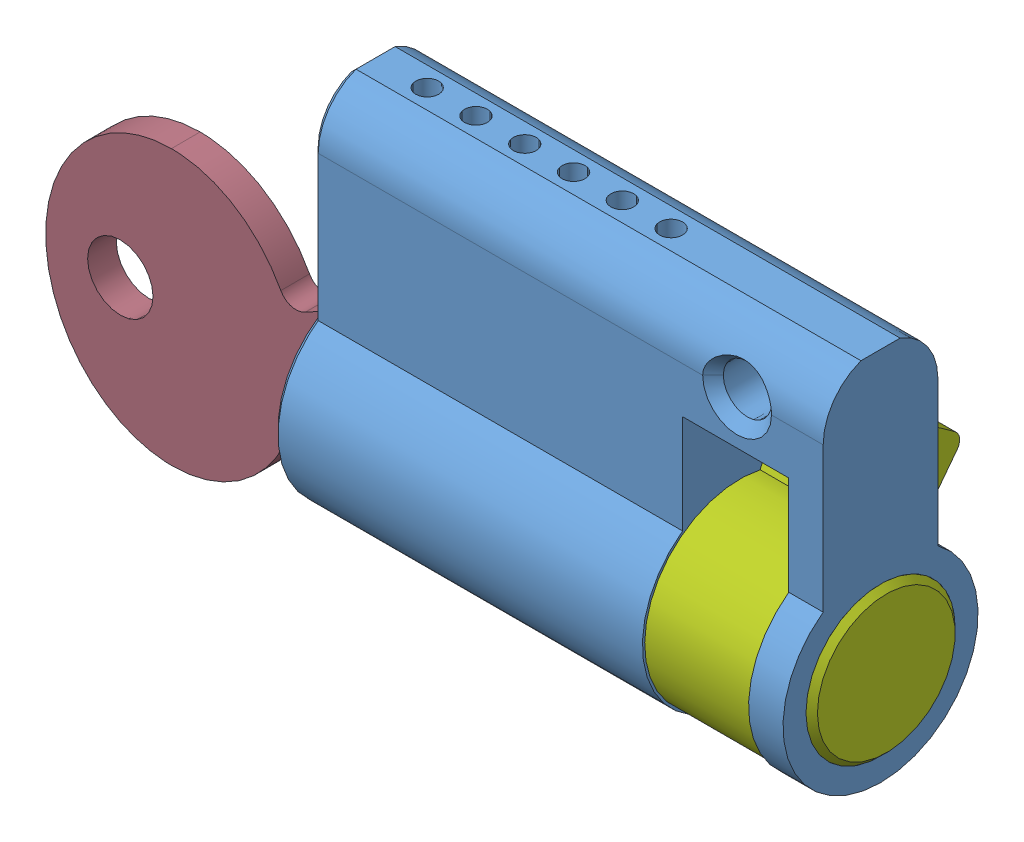
SolidWorks assembly lock_6-pin_assembly_eg, configuration Default. Lengths in mm.
Overall size (72.78 39.27 18.49).
16 component instances, 13 part files, 0 mates.
Components (placement in the parent):
- cylinder_6-pin_sub-assembly_e-1: cylinder_6-pin_sub-assembly_e [Default] at origin size (44.5 32.7 17)
  - cylinder_d_six-pair_of_pins-1: cylinder_d_six-pair_of_pins [Default] at origin size (44.5 32.7 17)
  - upper_half_pin_y_cut_depth_2-1: upper_half_pin_y_cut_depth_2 [Default] at (5 15.25 0) x (0.989024 0 0.147752) z (0 -1 0) size (2 2 8)
  - upper_half_pin_y_cut_depth_4-1: upper_half_pin_y_cut_depth_4 [Default] at (9.25 13.25 0) x (0.53788 0 0.843022) z (0 -1 0) size (2 2 6)
  - upper_half_pin_y_cut_depth_5-1: upper_half_pin_y_cut_depth_5 [Default] at (13.5 12.25 0) x (0.923388 0 0.383868) z (0 -1 0) size (2 2 5)
  - upper_half_pin_y_cut_depth_1-1: upper_half_pin_y_cut_depth_1 [Default] at (22 16.4 0) x (-0.223246 0 0.974762) z (0 -1 0) size (2 2 9.15)
  - upper_half_pin_y_cut_depth_3-1: upper_half_pin_y_cut_depth_3 [Default] at (26.25 14.25 0) x (-0.197827 0 0.980237) z (0 -1 0) size (2 2 7)
- core_6-pin_with_key_g-1: core_6-pin_with_key_g [Default] x (1 0 0) z (0 -0.003633 0.999993) size (72.78 29.23 18.24)
  - core_6-pin_sub-assembly_cxxxxxx-1: core_6-pin_sub-assembly_cxxxxxx [Default] at origin size (45.22 22.49 18.24)
    - core_c_six-pair_of_pins-1: core_c_six-pair_of_pins [Default] at origin size (45.22 22.49 18.24)
    - lower_half_pin_x-depth_2-1: lower_half_pin_x-depth_2 [Default] at (5 7.25 0) x (0.664735 0 0.74708) z (-0.74708 0 0.664735) size (2.04 6.1 2.04)
    - lower_half_pin_x-depth_4-1: lower_half_pin_x-depth_4 [Default] at (9.25 7.25 0) x (0.344742 0 0.938697) z (-0.938697 0 0.344742) size (2.04 8.1 2.04)
    - lower_half_pin_x-depth_5-1: lower_half_pin_x-depth_5 [Default] at (13.5 7.25 0) x (-0.232518 0 0.972592) z (-0.972592 0 -0.232518) size (2.04 9.1 2.04)
    - lower_half_pin_x-depth_1-1: lower_half_pin_x-depth_1 [Default] at (22 7.25 0) x (0.325076 0 0.945688) z (-0.945688 0 0.325076) size (2.04 5.25 2.04)
    - lower_half_pin_x-depth_3-1: lower_half_pin_x-depth_3 [Default] at (26.25 7.25 0) x (-0.36018 0 0.932883) z (-0.932883 0 -0.36018) size (2.04 7.1 2.04)
  - key_f-1: key_f [Default] at (0 -2.25 0) x (1 0 0) z (0 -1 0) size (60.37 2.5 25.58)
